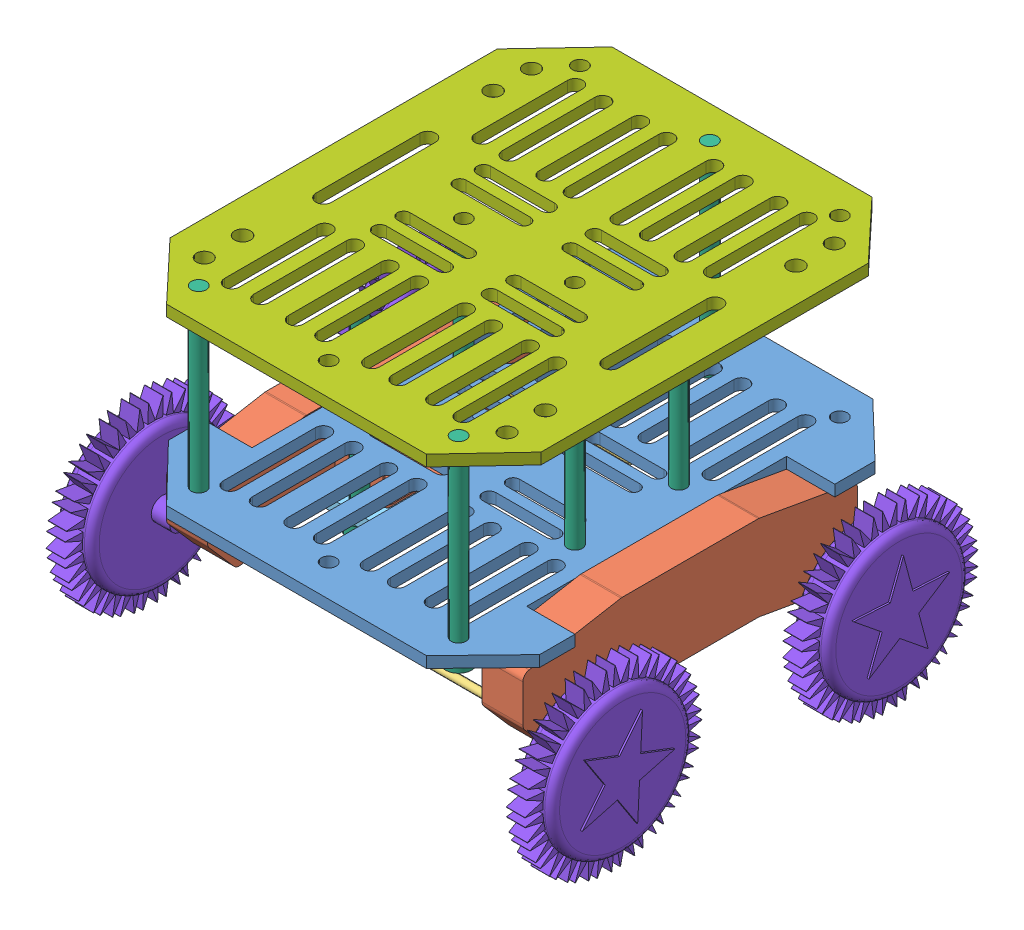
SolidWorks assembly 00 Rose, configuration Default. Lengths in mm.
Overall size (135 102.26 137.53).
23 component instances, 8 part files, 39 mates.
Components (placement in the parent):
- Rose - Bottom-1: Rose - Bottom [Default] at (101.7967 46.3979 73.0529) size (100 3 120)
- AssemGearbox_Motor-1: AssemGearbox_Motor [Default] at (-33.7212 -14.8797 -1.1009) size (50 26.13 90.18)
  - Rose - Motor_body-1: Rose - Motor_body [Default] at (19.8097 56.2296 70.3008) size (24 26.13 90.18)
  - Rose - Wheel_rod_lo-1: Rose - Wheel_rod_lo [Default] at (12.8097 42.2283 36.335) size (50 2 2)
  - Rose - Wheel_rod_sh-1: Rose - Wheel_rod_sh [Default] at (12.8097 42.2283 110.7577) size (10 2 2)
- Rose - Hinge-1: Rose - Hinge [Default] at (-70.0867 26.8979 106.364) size (13 3 35)
- AssemGearbox_Motor-2: AssemGearbox_Motor [Default] at (101.8981 -14.8797 145.9919) x (-1 0 0) z (0 0 -1) size (50 26.13 90.18)
  - Rose - Motor_body-1: Rose - Motor_body [Default] at (19.8097 56.2296 70.3008) size (24 26.13 90.18)
  - Rose - Wheel_rod_lo-1: Rose - Wheel_rod_lo [Default] at (12.8097 42.2283 36.335) size (50 2 2)
  - Rose - Wheel_rod_sh-1: Rose - Wheel_rod_sh [Default] at (12.8097 42.2283 110.7577) size (10 2 2)
- Rose - Hinge-2: Rose - Hinge [Default] at (-12.0867 26.8979 106.364) size (13 3 35)
- Rose - Nail-1: Rose - Nail [Default] at (34.0885 46.3979 19.1741) size (7 53 7)
- Rose - Nail-2: Rose - Nail [Default] at (63.0885 26.8979 84.5138) size (7 53 7)
- Rose - Nail-3: Rose - Nail [Default] at (63.0885 26.8979 56.5138) size (7 53 7)
- Rose - Nail-4: Rose - Nail [Default] at (5.0885 26.8979 84.5138) size (7 53 7)
- Rose - Nail-5: Rose - Nail [Default] at (5.0885 26.8979 56.5138) size (7 53 7)
- Rose - Nail-6: Rose - Nail [Default] at (-0.9115 46.3979 121.8536) size (7 53 7)
- Rose - Nail-7: Rose - Nail [Default] at (69.0885 46.3979 121.8536) size (7 53 7)
- Rose - Top-1: Rose - Top [Default] at (88.9231 93.3979 79.1466) size (99.95 3 120)
- Rose - Wheel-1: Rose - Wheel [Default] at (-32.9115 27.3485 35.2342) x (1 0 0) z (0 0.303876 0.952712) size (15.5 47.58 47.58)
- Rose - Wheel-2: Rose - Wheel [Default] at (-32.9115 27.3485 109.6569) x (1 0 0) z (0 0.031781 0.999495) size (15.5 47.58 47.58)
- Rose - Wheel-3: Rose - Wheel [Default] at (101.0885 27.3485 35.2342) x (-1 0 0) z (0 0 -1) size (15.5 47.58 47.58)
- Rose - Wheel-4: Rose - Wheel [Default] at (101.0885 27.3485 109.6569) x (-1 0 0) z (0 0.810879 -0.585214) size (15.5 47.58 47.58)
Mates (geometry in assembly coordinates):
- Coincident1: coincident anti-aligned: plane of Rose - Bottom-1 through (101.7967 46.3979 73.0529) normal (0 -1 0); plane of AssemGearbox_Motor-1/Rose - Motor_body-1 through (10.0885 46.3979 82.9455) normal (0 1 0)
- Coincident8: coincident anti-aligned: plane of Rose - Bottom-1 through (-2.9115 49.3979 35.5138) normal (-1 0 0); plane of AssemGearbox_Motor-1/Rose - Motor_body-1 through (-2.9115 41.3498 69.2) normal (1 0 0)
- Coincident9: coincident anti-aligned: plane of AssemGearbox_Motor-1/Rose - Motor_body-1 through (10.0885 29.8979 82.9455) normal (0 -1 0); plane of Rose - Hinge-1 through (-70.0867 29.8979 106.364) normal (0 1 0)
- Concentric1: concentric aligned: cylinder of Rose - Bottom-1 through (5.0885 49.3979 84.5138) axis (0 -1 0) radius 2; cylinder of Rose - Hinge-1 through (5.0885 29.8979 84.5138) axis (0 -1 0) radius 2
- Concentric2: concentric aligned: cylinder of Rose - Bottom-1 through (5.0885 49.3979 56.5138) axis (0 -1 0) radius 2; cylinder of Rose - Hinge-1 through (5.0885 29.8979 56.5138) axis (0 -1 0) radius 2
- Coincident10: coincident anti-aligned: plane of Rose - Bottom-1 through (101.7967 46.3979 73.0529) normal (0 -1 0); plane of AssemGearbox_Motor-2/Rose - Motor_body-1 through (58.0885 46.3979 61.9455) normal (0 1 0)
- Coincident11: coincident anti-aligned: plane of Rose - Bottom-1 through (71.0885 49.3979 35.5138) normal (1 0 0); plane of AssemGearbox_Motor-2/Rose - Motor_body-1 through (71.0885 41.3498 75.691) normal (-1 0 0)
- Coincident12: coincident anti-aligned: plane of AssemGearbox_Motor-2/Rose - Motor_body-1 through (58.0885 29.8979 61.9455) normal (0 -1 0); plane of Rose - Hinge-2 through (-12.0867 29.8979 106.364) normal (0 1 0)
- Concentric3: concentric aligned: cylinder of Rose - Bottom-1 through (63.0885 49.3979 84.5138) axis (0 -1 0) radius 2; cylinder of Rose - Hinge-2 through (63.0885 29.8979 84.5138) axis (0 -1 0) radius 2
- Concentric4: concentric aligned: cylinder of Rose - Bottom-1 through (63.0885 49.3979 56.5138) axis (0 -1 0) radius 2; cylinder of Rose - Hinge-2 through (63.0885 29.8979 56.5138) axis (0 -1 0) radius 2
- Concentric5: concentric aligned: cylinder of Rose - Bottom-1 through (34.0885 49.3979 19.1741) axis (0 -1 0) radius 2; cylinder of Rose - Nail-1 through (34.0885 96.3979 19.1741) axis (0 -1 0) radius 2
- Coincident13: coincident anti-aligned: plane of Rose - Bottom-1 through (101.7967 46.3979 73.0529) normal (0 -1 0); plane of Rose - Nail-1 through (34.0885 46.3979 19.1741) normal (0 1 0)
- Concentric6: concentric aligned: cylinder of Rose - Hinge-2 through (63.0885 29.8979 84.5138) axis (0 -1 0) radius 2; cylinder of Rose - Nail-2 through (63.0885 76.8979 84.5138) axis (0 -1 0) radius 2
- Coincident14: coincident anti-aligned: plane of Rose - Hinge-2 through (-12.0867 26.8979 106.364) normal (0 -1 0); plane of Rose - Nail-2 through (63.0885 26.8979 84.5138) normal (0 1 0)
- Concentric7: concentric aligned: cylinder of Rose - Hinge-2 through (63.0885 29.8979 56.5138) axis (0 -1 0) radius 2; cylinder of Rose - Nail-3 through (63.0885 76.8979 56.5138) axis (0 -1 0) radius 2
- Coincident15: coincident anti-aligned: plane of Rose - Hinge-2 through (-12.0867 26.8979 106.364) normal (0 -1 0); plane of Rose - Nail-3 through (63.0885 26.8979 56.5138) normal (0 1 0)
- Concentric8: concentric aligned: cylinder of Rose - Hinge-1 through (5.0885 29.8979 84.5138) axis (0 -1 0) radius 2; cylinder of Rose - Nail-4 through (5.0885 76.8979 84.5138) axis (0 -1 0) radius 2
- Concentric9: concentric aligned: cylinder of Rose - Hinge-1 through (5.0885 29.8979 56.5138) axis (0 -1 0) radius 2; cylinder of Rose - Nail-5 through (5.0885 76.8979 56.5138) axis (0 -1 0) radius 2
- Coincident16: coincident anti-aligned: plane of Rose - Hinge-1 through (-70.0867 26.8979 106.364) normal (0 -1 0); plane of Rose - Nail-5 through (5.0885 26.8979 56.5138) normal (0 1 0)
- Coincident17: coincident anti-aligned: plane of Rose - Hinge-1 through (-70.0867 26.8979 106.364) normal (0 -1 0); plane of Rose - Nail-4 through (5.0885 26.8979 84.5138) normal (0 1 0)
- Concentric10: concentric aligned: cylinder of Rose - Bottom-1 through (69.0885 49.3979 121.8536) axis (0 -1 0) radius 2; cylinder of Rose - Nail-7 through (69.0885 96.3979 121.8536) axis (0 -1 0) radius 2
- Concentric11: concentric aligned: cylinder of Rose - Bottom-1 through (-0.9115 49.3979 121.8536) axis (0 -1 0) radius 2; cylinder of Rose - Nail-6 through (-0.9115 96.3979 121.8536) axis (0 -1 0) radius 2
- Coincident18: coincident anti-aligned: plane of Rose - Bottom-1 through (101.7967 46.3979 73.0529) normal (0 -1 0); plane of Rose - Nail-6 through (-0.9115 46.3979 121.8536) normal (0 1 0)
- Coincident19: coincident anti-aligned: plane of Rose - Bottom-1 through (101.7967 46.3979 73.0529) normal (0 -1 0); plane of Rose - Nail-7 through (69.0885 46.3979 121.8536) normal (0 1 0)
- Parallel1: parallel aligned: plane of Rose - Bottom-1 through (101.7967 49.3979 73.0529) normal (0 1 0); plane of Rose - Top-1 through (88.9231 96.3979 79.1466) normal (0 1 0)
- Coincident21: coincident aligned: circle of Rose - Nail-6; plane of Rose - Top-1 through (88.9231 96.3979 79.1466) normal (0 1 0)
- Concentric12: concentric aligned: cylinder of Rose - Nail-6 through (-0.9115 96.3979 121.8536) axis (0 -1 0) radius 2; cylinder of Rose - Top-1 through (-0.9115 96.3979 121.8536) axis (0 -1 0) radius 2
- Concentric13: concentric aligned: cylinder of Rose - Nail-7 through (69.0885 96.3979 121.8536) axis (0 -1 0) radius 2; cylinder of Rose - Top-1 through (69.0885 96.3979 121.8536) axis (0 -1 0) radius 2
- Concentric14: concentric aligned: cylinder of Rose - Nail-1 through (34.0885 96.3979 19.1741) axis (0 -1 0) radius 2; cylinder of Rose - Top-1 through (34.0885 96.3979 19.1741) axis (0 -1 0) radius 2
- Coincident22: coincident aligned: plane of AssemGearbox_Motor-1/Rose - Motor_body-1 through (-2.9115 44.9594 27.3557) normal (0 0 -1); plane of AssemGearbox_Motor-2/Rose - Motor_body-1 through (71.0885 44.9594 27.3557) normal (0 0 -1)
- Coincident23: coincident: line of Rose - Bottom-1 through (71.0885 46.3979 35.5138) axis (1 0 0); plane of AssemGearbox_Motor-2/Rose - Motor_body-1 through (71.0885 49.6479 53.9455) normal (0 0.984808 -0.173648)
- Concentric15: concentric aligned: cylinder of AssemGearbox_Motor-1/Rose - Wheel_rod_lo-1 through (29.0885 27.3485 35.2342) axis (-1 0 0) radius 1; cylinder of Rose - Wheel-1 through (-17.9115 27.3485 35.2342) axis (-1 0 0) radius 1
- Distance1: distance = 2 mm anti-aligned: plane of Rose - Wheel-1 through (-22.9115 27.3485 35.2342) normal (1 0 0); plane of AssemGearbox_Motor-1/Rose - Wheel_rod_lo-1 through (-20.9115 27.3485 35.2342) normal (-1 0 0)
- Concentric16: concentric aligned: cylinder of AssemGearbox_Motor-1/Rose - Wheel_rod_sh-1 through (-10.9115 27.3485 109.6569) axis (-1 0 0) radius 1; cylinder of Rose - Wheel-2 through (-17.9115 27.3485 109.6569) axis (-1 0 0) radius 1
- Distance2: distance = 2 mm anti-aligned: plane of Rose - Wheel-2 through (-22.9115 27.3485 109.6569) normal (1 0 0); plane of AssemGearbox_Motor-1/Rose - Wheel_rod_sh-1 through (-20.9115 27.3485 109.6569) normal (-1 0 0)
- Concentric17: concentric aligned: cylinder of AssemGearbox_Motor-2/Rose - Wheel_rod_sh-1 through (79.0885 27.3485 35.2342) axis (1 0 0) radius 1; cylinder of Rose - Wheel-3 through (86.0885 27.3485 35.2342) axis (1 0 0) radius 1
- Distance3: distance = 2 mm anti-aligned: plane of AssemGearbox_Motor-2/Rose - Wheel_rod_sh-1 through (89.0885 27.3485 35.2342) normal (1 0 0); plane of Rose - Wheel-3 through (91.0885 27.3485 35.2342) normal (-1 0 0)
- Concentric18: concentric aligned: cylinder of AssemGearbox_Motor-2/Rose - Wheel_rod_lo-1 through (39.0885 27.3485 109.6569) axis (1 0 0) radius 1; cylinder of Rose - Wheel-4 through (86.0885 27.3485 109.6569) axis (1 0 0) radius 1
- Distance4: distance = 2 mm anti-aligned: plane of Rose - Wheel-4 through (91.0885 27.3485 109.6569) normal (-1 0 0); plane of AssemGearbox_Motor-2/Rose - Wheel_rod_lo-1 through (89.0885 27.3485 109.6569) normal (1 0 0)
